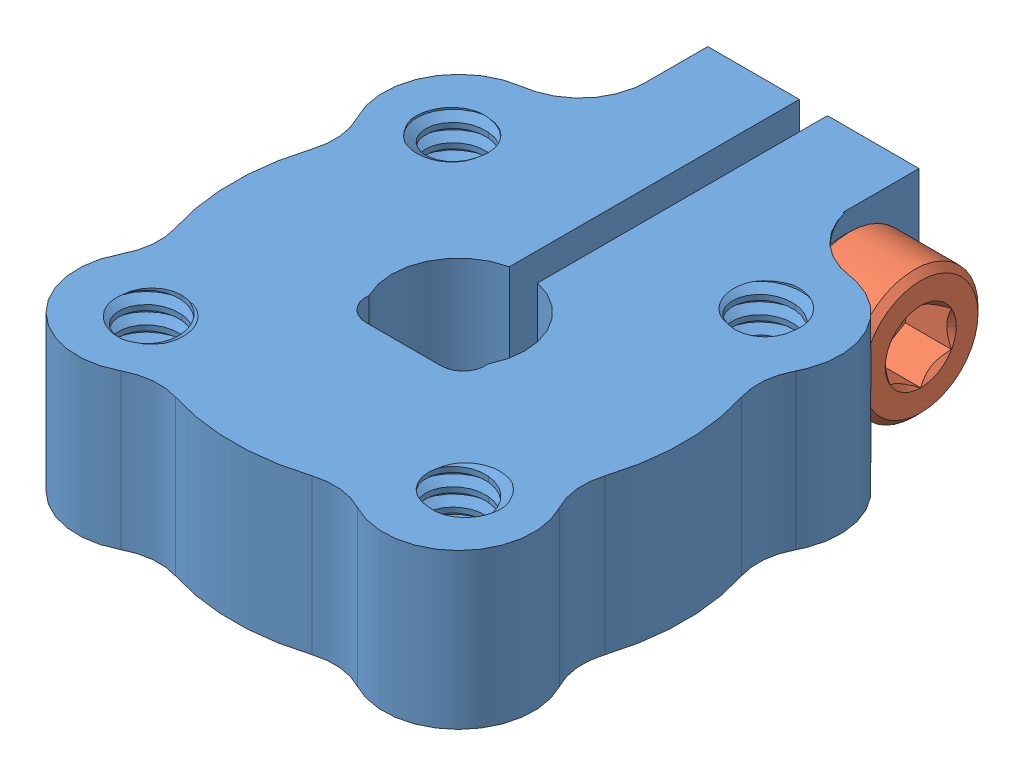
SolidWorks assembly 545618 assembly.step, configuration Default. Lengths in mm.
Overall size (20.57 9.53 26.29).
2 component instances, 2 part files, 0 mates.
Components (placement in the parent):
- 545618.step-1: 545618.step [Default] at (-35.5167 10.7278 10.9817) size (20.57 9.53 26.29)
- 632110_90128A121.step-1: 632110_90128A121.step [Default] at (-40.2792 16.7603 -1.5913) x (0 0 1) z (-1 0 0) size (5.74 5.74 13.04)
